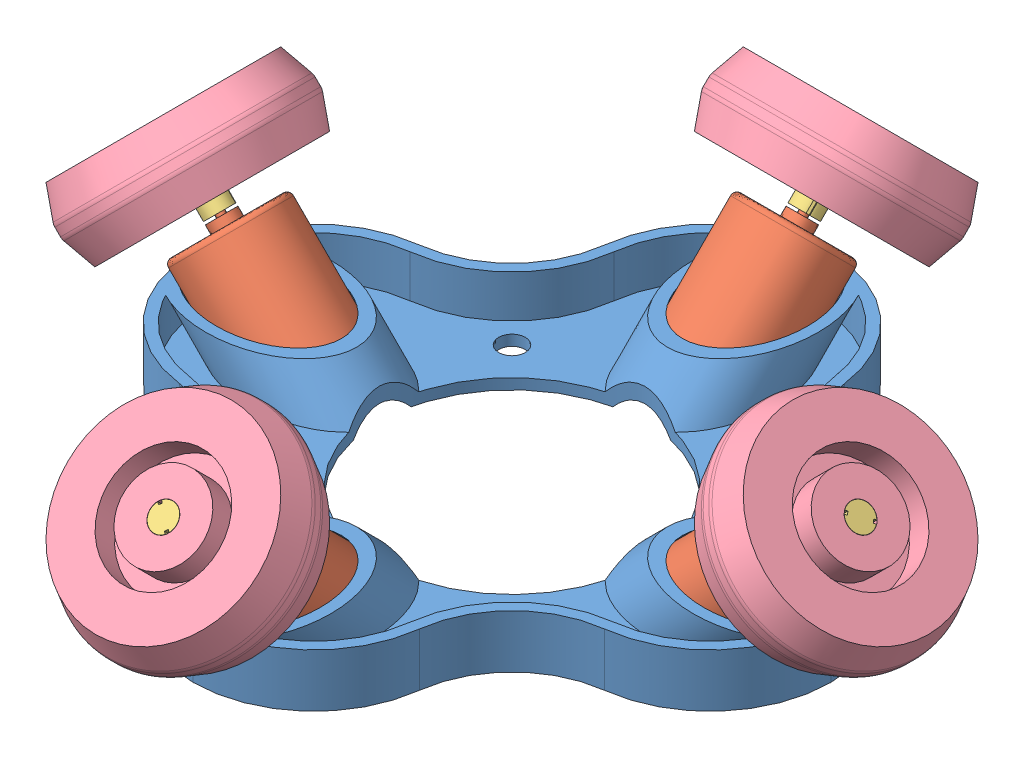
SolidWorks assembly SimpleBaseASM, configuration Default. Lengths in mm.
Overall size (202.53 75.33 202.53).
17 component instances, 4 part files, 6 mates.
Components (placement in the parent):
- SimpleBase-1: SimpleBase [Default] at (32.9115 49.7278 79.4177) size (152.4 15.38 152.4)
- SimpleMotorASM-1: SimpleMotorASM [Default] at (-20.3302 21.8371 63.1777) x (0 0 1) z (-0.707107 0.707107 0) size (50.8 50.8 56.46)
  - DC_Motor-1: DC_Motor [Default] at (16.24 25.168 15.283) size (24.38 24.38 45.03)
  - MotorShaft-1: MotorShaft [Default] at (16.24 25.168 67.6832) x (0.749535 -0.661965 0) z (0.661965 0.749535 0) size (6.3 19.05 6.35)
  - Omni_Wheel-1: Omni_Wheel [Default] at (16.24 25.168 59.4282) size (50.8 50.8 16.51)
- SimpleMotorASM-2: SimpleMotorASM [Default] at (49.1515 21.8371 26.1759) x (-1 0 0) z (0 0.707107 -0.707107) size (50.8 50.8 56.46)
  - DC_Motor-1: DC_Motor [Default] at (16.24 25.168 15.283) size (24.38 24.38 45.03)
  - MotorShaft-1: MotorShaft [Default] at (16.24 25.168 67.6832) x (0.749535 -0.661965 0) z (0.661965 0.749535 0) size (6.3 19.05 6.35)
  - Omni_Wheel-1: Omni_Wheel [Default] at (16.24 25.168 59.4282) size (50.8 50.8 16.51)
- SimpleMotorASM-3: SimpleMotorASM [Default] at (86.1533 21.8371 95.6576) x (0 0 -1) z (0.707107 0.707107 0) size (50.8 50.8 56.46)
  - DC_Motor-1: DC_Motor [Default] at (16.24 25.168 15.283) size (24.38 24.38 45.03)
  - MotorShaft-1: MotorShaft [Default] at (16.24 25.168 67.6832) x (0.749535 -0.661965 0) z (0.661965 0.749535 0) size (6.3 19.05 6.35)
  - Omni_Wheel-1: Omni_Wheel [Default] at (16.24 25.168 59.4282) size (50.8 50.8 16.51)
- SimpleMotorASM-4: SimpleMotorASM [Default] at (16.6716 21.8371 132.6594) x (1 0 0) z (0 0.707107 0.707107) size (50.8 50.8 56.46)
  - DC_Motor-1: DC_Motor [Default] at (16.24 25.168 15.283) size (24.38 24.38 45.03)
  - MotorShaft-1: MotorShaft [Default] at (16.24 25.168 67.6832) x (0.749535 -0.661965 0) z (0.661965 0.749535 0) size (6.3 19.05 6.35)
  - Omni_Wheel-1: Omni_Wheel [Default] at (16.24 25.168 59.4282) size (50.8 50.8 16.51)
Mates (geometry in assembly coordinates):
- Concentric1: concentric anti-aligned: cylinder of SimpleBase-1 through (42.666 19.8338 79.4177) axis (-0.707107 0.707107 0) radius 12.3825; cylinder of ? through (-9.7266 72.2264 79.4177) axis (0.707107 -0.707107 0) radius 12.192
- Perpendicular1: perpendicular: plane of SimpleBase-1 through (-0.959 49.7278 79.4177) normal (0 -1 0); plane of ? through (9.2397 41.8732 77.8175) normal (0 0 -1)
- Coincident3: coincident anti-aligned: plane of SimpleBase-1 through (13.8615 49.7278 60.3677) normal (-0.707107 0.707107 0); plane of ? through (13.3168 49.1831 79.4177) normal (0.707107 -0.707107 0)
- Concentric3: concentric anti-aligned: cylinder of SimpleBase-1 through (17.266 19.8338 79.4177) axis (-0.707107 0.707107 0) radius 12.3825; cylinder of SimpleMotorASM-1/DC_Motor-1 through (-35.1266 72.2264 79.4177) axis (0.707107 -0.707107 0) radius 12.192
- Coincident4: coincident anti-aligned: plane of SimpleBase-1 through (-11.5385 49.7278 34.9677) normal (-0.707107 0.707107 0); plane of SimpleMotorASM-1/DC_Motor-1 through (-12.0832 49.1831 79.4177) normal (0.707107 -0.707107 0)
- Perpendicular2: perpendicular: plane of SimpleBase-1 through (-14.4089 49.7278 79.4177) normal (0 -1 0); plane of SimpleMotorASM-1/DC_Motor-1 through (-16.1603 41.8732 77.8175) normal (0 0 -1)
